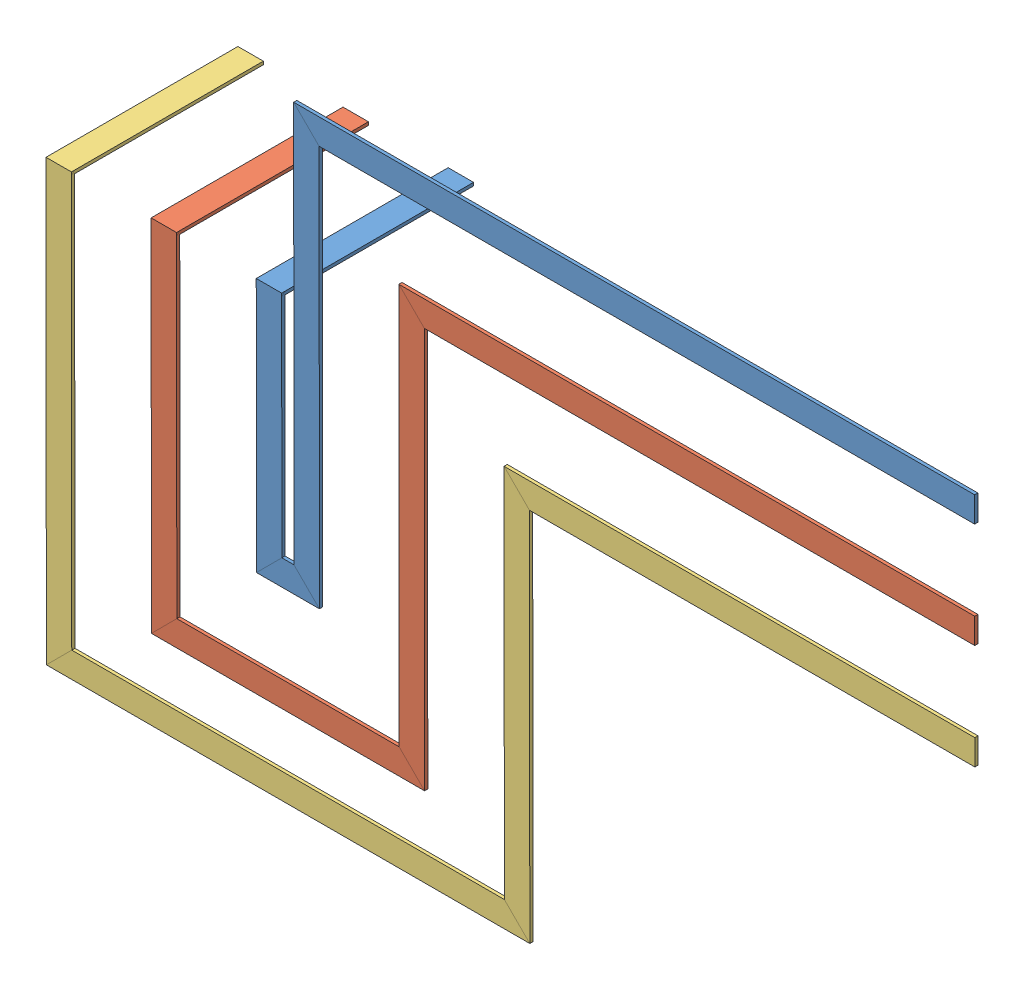
SolidWorks assembly PLACAS PARA VD4 SUBESTACIÓN SEC., configuration Predeterminado. Lengths in mm.
Overall size (1856.34 1221.44 383.35).
15 component instances, 7 part files, 0 mates.
Components (placement in the parent):
- AA- TERMINAL VD4 1.1-1: AA- TERMINAL VD4 1.1 [Predeterminado] at (89.1236 392.0496 1951.0008) x (-0.998394 0.056647 0) z (0 0 1) size (15 85 380) (hidden)
- AA- TERMINAL VD4 1.1-2: AA- TERMINAL VD4 1.1 [Predeterminado] at (669.2837 380.2818 1942.7058) x (-1 0 0) z (0 0 1) size (15 85 380) (hidden)
- Copia de Pieza8^PLACAS PARA VD4 SUBESTACIÓN SEC.-1: Copia de Pieza8^PLACAS PARA VD4 SUBESTACIÓN SEC. [Predeterminado] at (332.7505 50.5601 2027.0471) size (90.81 28.32 85.11) (hidden, virtual)
- AA- PLACA VDA 1.2-1: AA- PLACA VDA 1.2 [Predeterminado] at (268.7809 459.8889 1947.5383) x (-0.975303 -0.22087 0) z (0 0 1) size (15 140 372) (hidden)
- AA- PLACA VDA 1.2-2: AA- PLACA VDA 1.2 [Predeterminado] at (886.2891 464.5282 1955.0301) x (-0.998747 0.004326 -0.049855) z (-0.050033 -0.066991 0.996498) size (15 140 372) (hidden)
- AA-VD4 CONEXIONES ENSAMBLE-1: AA-VD4 CONEXIONES ENSAMBLE [Predeterminado] at (18.8957 90.9637 3366.3968) x (-1 -0.000778 0) z (0 0 -1) size (1855.39 1220 383.35)
  - AA- PLACA VD4-1: AA- PLACA VD4 [Predeterminado] at (337.0094 -191.1817 1345.3917) size (1435.39 850.8 383.35)
  - AA CONEXIÓN PLACA 2-1: AA CONEXIÓN PLACA 2 [Predeterminado] at (-100.6373 -155.5907 1369.1245) size (1645.39 850.8 383.35)
  - AA- CONEXIÓN PLACA 3-1: AA- CONEXIÓN PLACA 3 [Predeterminado] at (-47.7217 -340.9711 1384.1968) size (1855.39 877.77 383.35)
- AA- PLACA VDA 1.2-3: AA- PLACA VDA 1.2 [Predeterminado] at (956.93 299.9887 1875.3708) x (0.996171 -0.07497 0.044977) z (-0.050033 -0.066991 0.996498) size (15 140 372) (hidden)
- AA- TERMINAL VD4 1.1-3: AA- TERMINAL VD4 1.1 [Predeterminado] at (753.7143 310.2997 1869.6093) x (0.999745 -0.022569 0) z (0 0 1) size (15 85 380) (hidden)
- AA- PLACA VDA 1.2-4: AA- PLACA VDA 1.2 [Predeterminado] at (350.0688 309.5026 1877.4906) x (0.974644 0.223763 0) z (0 0 1) size (15 140 372) (hidden)
- AA- TERMINAL VD4 1.1-4: AA- TERMINAL VD4 1.1 [Predeterminado] at (139.2913 321.4792 1876.0299) x (0.998543 0.053961 0) z (0 0 1) size (15 85 380) (hidden)
- CONEXION VD 4 PAX-1: CONEXION VD 4 PAX [Predeterminado] at (554.126 321.3054 1590.2406) size (15 15 350) (hidden)
- CONEXION VD 4 PAX-2: CONEXION VD 4 PAX [Predeterminado] at (-87.6902 319.8394 1594.8083) size (15 15 350) (hidden)
